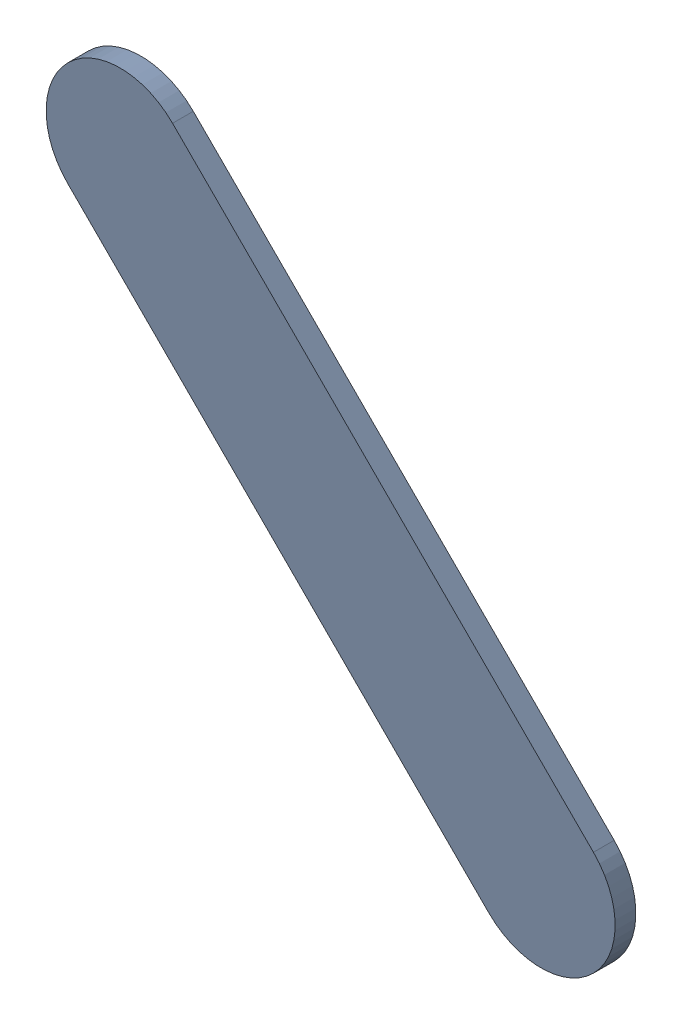
SolidWorks assembly Track (13.178mm,24.472mm)(13.9mm,23.75mm) on Top Layer, configuration Predeterminado. Lengths in mm.
Overall size (0.98 0.98 0.04).
2 component instances, 1 part files, 0 mates.
Components (placement in the parent):
- Track (13.178mm,24.472mm)(13.9mm,23.75mm) on Top Layer-1-1: Track (13.178mm,24.472mm)(13.9mm,23.75mm) on Top Layer-1 [Predeterminado] at (-68.317 -44.187 -0.0457) size (0.98 0.98 0.04)
  - Track (13.178mm,24.472mm)(13.9mm,23.75mm) on Top Layer-Part-1-1: Track (13.178mm,24.472mm)(13.9mm,23.75mm) on Top Layer-Part-1 [Predeterminado] at origin size (0.98 0.98 0.04)
